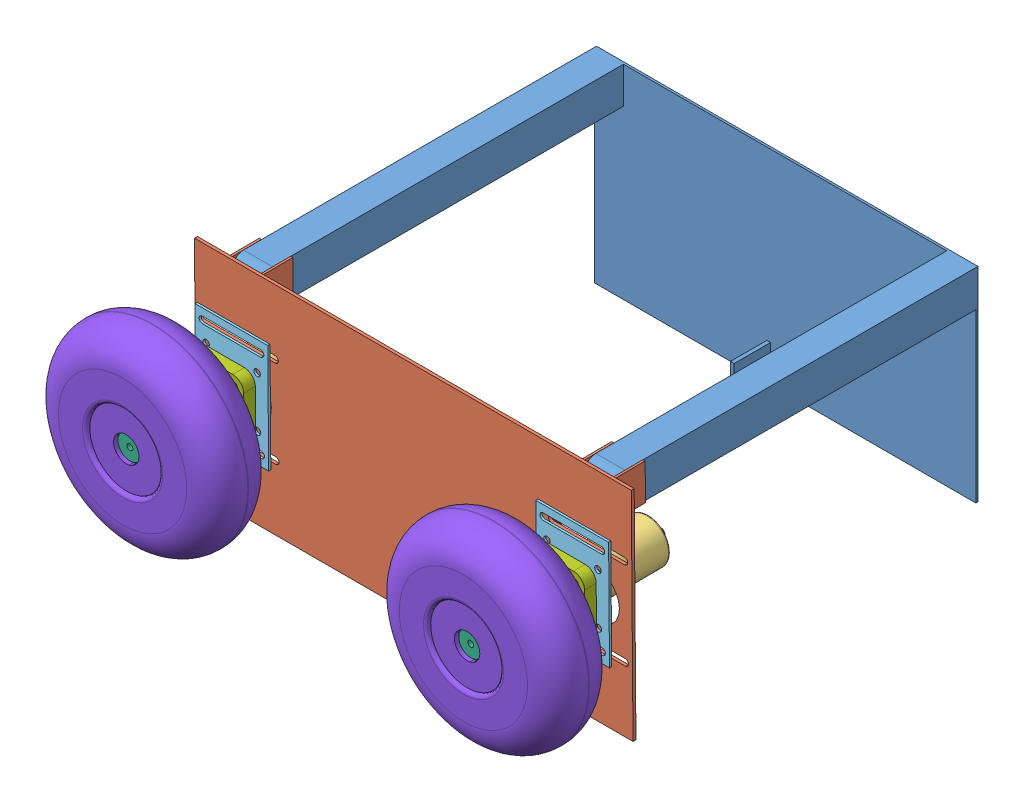
SolidWorks assembly Assemblage totale, configuration Défaut. Lengths in mm.
Overall size (827.9 361.9 667.52).
18 component instances, 10 part files, 11 mates.
Components (placement in the parent):
- support chassie-1: support chassie [Défaut] at (-208.57 -255.8772 -153.4951) size (524 280 500)
- chassie-1: chassie [Défaut] at (-770.57 -546.1033 358.3582) x (0 -0.999967 -0.008097) z (0 0.008097 -0.999967) size (300 600 54)
- Assemblage moteur roue axe tole-1: Assemblage moteur roue axe tole [Défaut] at (-718.1954 -397.997 180.5516) x (0 0.999967 0.008097) z (0 -0.008097 0.999967) size (359.72 359.72 271.5)
  - moteur ok-1: moteur ok [Défaut] at (3.3383 -0.7364 77.5) size (60 60 121)
  - axe de moteur-1: axe de moteur [Défaut] at (3.3383 -0.7364 131.5) x (-0.999951 0.009877 0) z (0 0 1) size (8 8 72.2)
  - piece support moteur 2-1: piece support moteur 2 [Défaut] at (78.3383 49.2636 179) size (150 100 3)
  - axe moteur jusqua roue 2-1: axe moteur jusqua roue 2 [Défaut] at (3.3383 -0.7364 163.7) x (0.99006 -0.140645 0) z (0 0 1) size (39 39 138.3)
  - palier 4 fixations-1: palier 4 fixations [Défaut] at (-44.1617 -48.2364 196.95) size (95 95 35.8)
  - roue-1: roue [Défaut] at (3.3383 -0.7364 247) x (-0.838279 0.545242 0) z (0 0 1) size (260 260 85)
- Assemblage moteur roue axe tole-2: Assemblage moteur roue axe tole [Défaut] at (-248.5405 -391.3206 180.6057) x (0 -0.999967 -0.008097) z (0 -0.008097 0.999967) size (359.72 359.72 271.5)
  - moteur ok-1: moteur ok [Défaut] at (3.3383 -0.7364 77.5) size (60 60 121)
  - axe de moteur-1: axe de moteur [Défaut] at (3.3383 -0.7364 131.5) x (-0.999951 0.009877 0) z (0 0 1) size (8 8 72.2)
  - piece support moteur 2-1: piece support moteur 2 [Défaut] at (78.3383 49.2636 179) size (150 100 3)
  - axe moteur jusqua roue 2-1: axe moteur jusqua roue 2 [Défaut] at (3.3383 -0.7364 163.7) x (0.99006 -0.140645 0) z (0 0 1) size (39 39 138.3)
  - palier 4 fixations-1: palier 4 fixations [Défaut] at (-44.1617 -48.2364 196.95) size (95 95 35.8)
  - roue-1: roue [Défaut] at (3.3383 -0.7364 247) x (-0.838279 0.545242 0) z (0 0 1) size (260 260 85)
- verin 1-2: verin 1 [Défaut] at (-470.57 -510.8773 -133.4951) x (1 0 0) z (0 0.000017 1) size (40 40 300)
- verin 2-1: verin 2 [Défaut] at (-470.57 -510.8763 -72.3575) x (0 -1 0.000017) z (0 0.000017 1) size (36 36 410)
Mates (geometry in assembly coordinates):
- Coïncidente1: coincident anti-aligned: plane of support chassie-1 through (-248.57 -535.8772 346.5049) normal (-1 0 0); plane of chassie-1 through (-248.57 -255.6756 306.7081) normal (1 0 0)
- Coaxiale3: concentric anti-aligned: circle of support chassie-1; circle of chassie-1
- Coïncidente6: coincident aligned: line of chassie-1 through (-660.57 -331.1104 360.0991) axis (-1 0 0); line of Assemblage moteur roue axe tole-1/piece support moteur 2-1 through (-677.4591 -331.1104 360.0991) axis (-1 0 0)
- Coïncidente4: coincident anti-aligned: plane of chassie-1 through (-770.57 -546.1033 358.3582) normal (0 -0.008097 0.999967); plane of Assemblage moteur roue axe tole-1/piece support moteur 2-1 through (-767.4591 -321.1107 360.18) normal (0 0.008097 -0.999967)
- Coïncidente7: coincident anti-aligned: plane of chassie-1 through (-770.57 -546.1033 358.3582) normal (0 -0.008097 0.999967); plane of Assemblage moteur roue axe tole-2/piece support moteur 2-1 through (-199.2769 -471.1058 358.9655) normal (0 0.008097 -0.999967)
- Coïncidente9: coincident aligned: line of chassie-1 through (-180.57 -331.1104 360.0991) axis (-1 0 0); line of Assemblage moteur roue axe tole-2/piece support moteur 2-1 through (-209.2769 -331.1104 360.0991) axis (-1 0 0)
- Tangent7: tangent anti-aligned: plane of support chassie-1 through (-490.57 -535.8772 -100.4951) normal (1 0 0); cylinder of verin 1-2 through (-470.57 -510.8723 166.5049) axis (0 -0.000017 -1) radius 20
- Tangent8: tangent: circle of support chassie-1; curve of verin 1-2
- Coaxiale4: concentric anti-aligned: cylinder of support chassie-1 through (-208.57 -510.8772 -125.4951) axis (-1 0 0) radius 4.5; cylinder of verin 1-2 through (-490.57 -510.8772 -125.4951) axis (1 0 0) radius 4.5
- Coaxiale11: concentric anti-aligned: cylinder of verin 1-2 through (-470.57 -510.8765 -83.4951) axis (0 0.000017 1) radius 18; cylinder of verin 2-1 through (-470.57 -510.8695 337.6425) axis (0 -0.000017 -1) radius 18
- Coaxiale12: concentric anti-aligned: cylinder of chassie-1 through (-170.57 -510.8696 329.6425) axis (-1 0 0) radius 4.5; cylinder of verin 2-1 through (-488.57 -510.8696 329.6425) axis (1 0 0) radius 4.5
